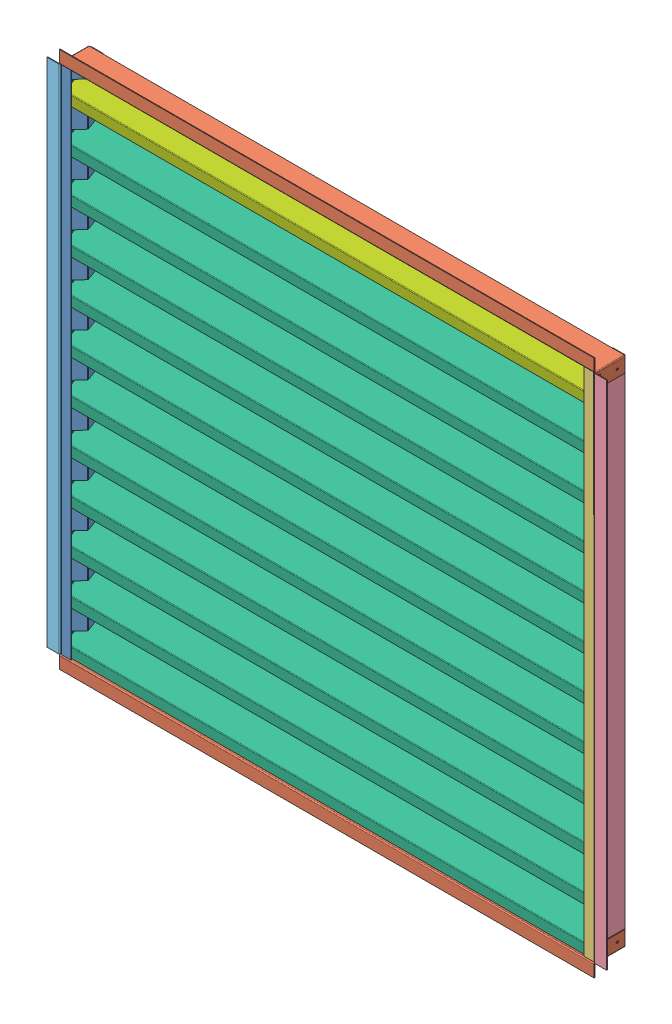
SolidWorks assembly Kifaru 2_louver_ASM, configuration Default. Lengths in mm.
Overall size (1145.4 1050 61.31).
18 component instances, 7 part files, 21 mates.
Components (placement in the parent):
- PRT_0041-M_Ex_Split_Carriage-B-1: PRT_0041-M_Ex_Split_Carriage-B [Default] at (-495.9256 608.5222 -6.0207) size (25.31 1000.01 58.38)
- PRT_0042-M_Ex_Louver_Frame_Beam.-1: PRT_0042-M_Ex_Louver_Frame_Beam. [Default] at (319.1744 -601.1778 -5.3841) size (1050.01 54.01 58.84)
- PRT_0040-M_Ex_Split_Carriage-A-1: PRT_0040-M_Ex_Split_Carriage-A [Default] at (318.2744 608.5222 -6.0207) size (25.31 1000.01 58.38)
- -PRT_0043-M_Ex_Louver_Frame_A-1: -PRT_0043-M_Ex_Louver_Frame_A [Default] at (318.8744 608.5222 -6.1207) size (74.01 1000.01 61.31)
- -PRT_0044-M_Ex_Louver_Frame_B-1: -PRT_0044-M_Ex_Louver_Frame_B [Default] at (-545.9256 608.5222 -6.1207) size (74.01 1000.01 61.31)
- PRT_0042-M_Ex_Louver_Frame_Beam.-2: PRT_0042-M_Ex_Louver_Frame_Beam. [Default] at (595.454 610.9179 -5.3841) x (-1 0 0) z (0 0 1) size (1050.01 54.01 58.84)
- -PRT_0045-M_Ex_LoUVER_SPLIT_MID-1: -PRT_0045-M_Ex_LoUVER_SPLIT_MID [Default] at (457.3142 367.114 52.2427) size (1030 93.44 56.42)
- -PRT_0045-M_Ex_LoUVER_SPLIT_MID-2: -PRT_0045-M_Ex_LoUVER_SPLIT_MID [Default] at (457.3142 282.114 52.2427) size (1030 93.44 56.42)
- -PRT_0045-M_Ex_LoUVER_SPLIT_MID-3: -PRT_0045-M_Ex_LoUVER_SPLIT_MID [Default] at (457.3142 197.114 52.2427) size (1030 93.44 56.42)
- -PRT_0045-M_Ex_LoUVER_SPLIT_MID-4: -PRT_0045-M_Ex_LoUVER_SPLIT_MID [Default] at (457.3142 112.114 52.2427) size (1030 93.44 56.42)
- -PRT_0045-M_Ex_LoUVER_SPLIT_MID-5: -PRT_0045-M_Ex_LoUVER_SPLIT_MID [Default] at (457.3142 27.114 52.2427) size (1030 93.44 56.42)
- -PRT_0045-M_Ex_LoUVER_SPLIT_MID-6: -PRT_0045-M_Ex_LoUVER_SPLIT_MID [Default] at (457.3142 -57.886 52.2427) size (1030 93.44 56.42)
- -PRT_0045-M_Ex_LoUVER_SPLIT_MID-7: -PRT_0045-M_Ex_LoUVER_SPLIT_MID [Default] at (457.3142 -142.886 52.2427) size (1030 93.44 56.42)
- -PRT_0045-M_Ex_LoUVER_SPLIT_MID-8: -PRT_0045-M_Ex_LoUVER_SPLIT_MID [Default] at (457.3142 -227.886 52.2427) size (1030 93.44 56.42)
- -PRT_0045-M_Ex_LoUVER_SPLIT_MID-9: -PRT_0045-M_Ex_LoUVER_SPLIT_MID [Default] at (457.3142 -312.886 52.2427) size (1030 93.44 56.42)
- -PRT_0045-M_Ex_LoUVER_SPLIT_MID-10: -PRT_0045-M_Ex_LoUVER_SPLIT_MID [Default] at (457.3142 -397.886 52.2427) size (1030 93.44 56.42)
- -PRT_0045-M_Ex_LoUVER_SPLIT_MID-11: -PRT_0045-M_Ex_LoUVER_SPLIT_MID [Default] at (457.3142 -482.886 52.2427) size (1030 93.44 56.42)
- -PRT_0046-M_Ex_LoUVER_SPLIT_TOP-1: -PRT_0046-M_Ex_LoUVER_SPLIT_TOP [Default] at (457.3142 452.114 52.2427) size (1030 63.9 51.21)
Mates (geometry in assembly coordinates):
- Coincident1: coincident: plane of PRT_0041-M_Ex_Split_Carriage-B-1 through (-65.0858 -495.1299 44.3641) normal (-1 0 0); plane of -PRT_0044-M_Ex_Louver_Frame_B-1 through (-65.0858 609.8701 -4.3841) normal (1 0 0)
- Coincident4: coincident: plane of PRT_0041-M_Ex_Split_Carriage-B-1 through (-52.8358 -495.1299 -4.8207) normal (0 0 -1); plane of -PRT_0044-M_Ex_Louver_Frame_B-1 through (-53.0175 -495.1299 -4.8207) normal (0 0 1)
- Coincident5: coincident: plane of PRT_0041-M_Ex_Split_Carriage-B-1 through (-41.5224 504.8701 -4.1707) normal (0 1 0); plane of -PRT_0044-M_Ex_Louver_Frame_B-1 through (-41.3858 504.8701 -5.4707) normal (0 1 0)
- Coincident6: coincident: plane of PRT_0042-M_Ex_Louver_Frame_Beam.-1 through (1259.5776 518.5384 55.1793) normal (0 0 1); plane of -PRT_0044-M_Ex_Louver_Frame_B-1 through (-90.3858 609.8701 55.1793) normal (0 0 1)
- Coincident7: coincident: plane of PRT_0042-M_Ex_Louver_Frame_Beam.-1 through (596.8142 504.8701 53.1427) normal (0 -1 0); plane of -PRT_0044-M_Ex_Louver_Frame_B-1 through (-41.3858 504.8701 -5.4707) normal (0 1 0)
- Coincident8: coincident: plane of PRT_0042-M_Ex_Louver_Frame_Beam.-1 through (-66.3858 476.1701 25.1159) normal (1 0 0); plane of -PRT_0044-M_Ex_Louver_Frame_B-1 through (-66.3858 609.8701 -4.3841) normal (-1 0 0)
- Coincident10: coincident: plane of PRT_0042-M_Ex_Louver_Frame_Beam.-1 through (981.0142 490.3018 53.8793) normal (-1 0 0); plane of -PRT_0043-M_Ex_Louver_Frame_A-1 through (981.0142 -600.1299 -4.3841) normal (1 0 0)
- Coincident11: coincident: plane of PRT_0042-M_Ex_Louver_Frame_Beam.-1 through (1259.5776 518.5384 55.1793) normal (0 0 1); plane of -PRT_0043-M_Ex_Louver_Frame_A-1 through (1005.0142 -600.1299 55.1793) normal (0 0 1)
- Coincident12: coincident: plane of PRT_0042-M_Ex_Louver_Frame_Beam.-1 through (596.8142 504.8701 53.1427) normal (0 -1 0); plane of -PRT_0043-M_Ex_Louver_Frame_A-1 through (981.7508 504.8701 54.5293) normal (0 1 0)
- Coincident13: coincident: plane of PRT_0040-M_Ex_Split_Carriage-A-1 through (967.4642 -495.1299 -4.8207) normal (0 0 -1); plane of -PRT_0043-M_Ex_Louver_Frame_A-1 through (967.6459 -1705.1299 -4.8207) normal (0 0 1)
- Coincident14: coincident: plane of PRT_0040-M_Ex_Split_Carriage-A-1 through (979.7142 -495.1299 44.3641) normal (1 0 0); plane of -PRT_0043-M_Ex_Louver_Frame_A-1 through (979.7142 -600.1299 -4.3841) normal (-1 0 0)
- Coincident15: coincident: plane of PRT_0042-M_Ex_Louver_Frame_Beam.-1 through (596.8142 504.8701 53.1427) normal (0 -1 0); plane of PRT_0040-M_Ex_Split_Carriage-A-1 through (955.2503 504.8701 30.4608) normal (0 1 0)
- Coincident16: coincident: plane of -PRT_0044-M_Ex_Louver_Frame_B-1 through (-90.3858 609.8701 55.1793) normal (0 0 1); plane of PRT_0042-M_Ex_Louver_Frame_Beam.-2 through (-344.9492 -508.7982 55.1793) normal (0 0 1)
- Coincident17: coincident: plane of -PRT_0044-M_Ex_Louver_Frame_B-1 through (-65.0858 -495.1299 24.3793) normal (0 -1 0); plane of PRT_0042-M_Ex_Louver_Frame_Beam.-2 through (317.8142 -495.1299 53.1427) normal (0 1 0)
- Coincident18: coincident: plane of -PRT_0044-M_Ex_Louver_Frame_B-1 through (-66.3858 609.8701 -4.3841) normal (-1 0 0); plane of PRT_0042-M_Ex_Louver_Frame_Beam.-2 through (-66.3858 -480.5616 53.8793) normal (1 0 0)
- Width1: width: plane of -PRT_0045-M_Ex_LoUVER_SPLIT_MID-1 through (457.3142 373.9055 56.9638) normal (0 0.866025 0.5); plane of -PRT_0045-M_Ex_LoUVER_SPLIT_MID-1 through (457.3142 372.8663 56.3638) normal (0 -0.866025 -0.5); plane of PRT_0041-M_Ex_Split_Carriage-B-1 through (-391.7858 386.2384 36.4026) normal (0 -0.866025 -0.5); plane of PRT_0041-M_Ex_Split_Carriage-B-1 through (-391.7858 405.0523 -0.1841) normal (0 0.866025 0.5)
- Coincident19: coincident: plane of PRT_0041-M_Ex_Split_Carriage-B-1 through (-53.9175 -495.1299 52.2427) normal (0 0 -1); plane of -PRT_0045-M_Ex_LoUVER_SPLIT_MID-1 through (457.3142 367.114 52.2427) normal (0 0 1)
- Width2: width: plane of -PRT_0045-M_Ex_LoUVER_SPLIT_MID-1 through (-57.6858 376.9776 51.6427) normal (-1 0 0); plane of -PRT_0045-M_Ex_LoUVER_SPLIT_MID-1 through (972.3142 404.5662 3.8579) normal (1 0 0); plane of PRT_0041-M_Ex_Split_Carriage-B-1 through (-39.7858 -495.1299 10.4425) normal (1 0 0); plane of PRT_0040-M_Ex_Split_Carriage-A-1 through (954.4142 -495.1299 10.4425) normal (-1 0 0)
- Width3: width: plane of -PRT_0046-M_Ex_LoUVER_SPLIT_TOP-1 through (457.3142 458.9055 56.9638) normal (0 0.866025 0.5); plane of -PRT_0046-M_Ex_LoUVER_SPLIT_TOP-1 through (457.3142 457.8663 56.3638) normal (0 -0.866025 -0.5); plane of PRT_0041-M_Ex_Split_Carriage-B-1 through (-39.7858 483.0799 11.8925) normal (0 0.866025 0.5); plane of PRT_0041-M_Ex_Split_Carriage-B-1 through (-40.4358 478.4169 23.9691) normal (0 -0.866025 -0.5)
- Coincident20: coincident aligned: plane of -PRT_0045-M_Ex_LoUVER_SPLIT_MID-1 through (457.3142 367.114 52.2427) normal (0 0 1); plane of -PRT_0046-M_Ex_LoUVER_SPLIT_TOP-1 through (457.3142 452.114 52.2427) normal (0 0 1)
- Width4: width: plane of -PRT_0046-M_Ex_LoUVER_SPLIT_TOP-1 through (-57.6858 461.9776 51.6427) normal (-1 0 0); plane of -PRT_0046-M_Ex_LoUVER_SPLIT_TOP-1 through (972.3142 489.5662 3.8579) normal (1 0 0); plane of -PRT_0043-M_Ex_Louver_Frame_A-1 through (981.0142 -600.1299 -4.3841) normal (1 0 0); plane of -PRT_0044-M_Ex_Louver_Frame_B-1 through (-66.3858 609.8701 -4.3841) normal (-1 0 0)
